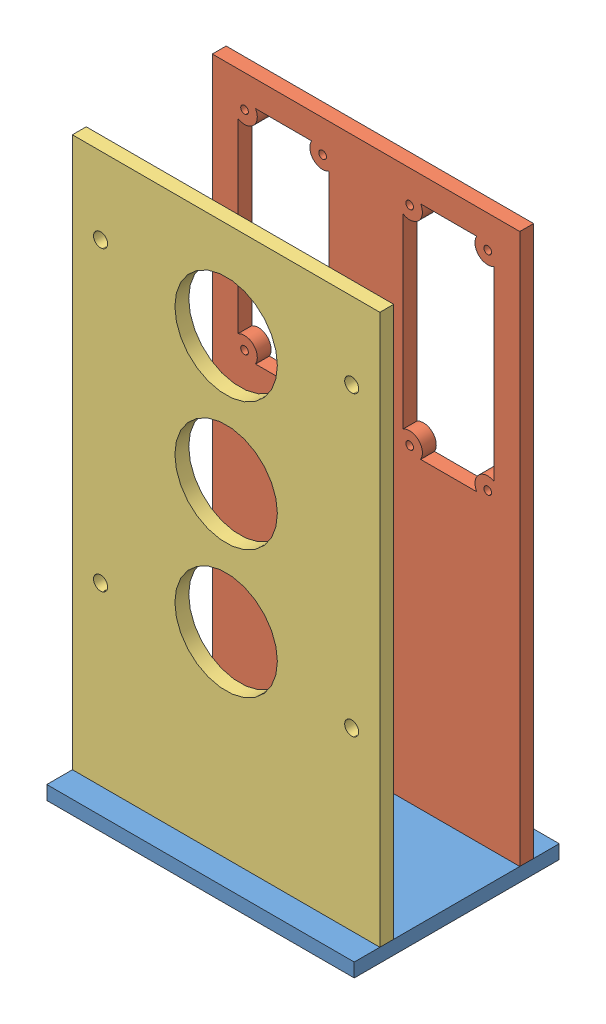
SolidWorks assembly rasp_ard_assem, configuration Varsayılan. Lengths in mm.
Overall size (60 110 40).
3 component instances, 3 part files, 6 mates.
Components (placement in the parent):
- Base-1: Base [Varsayılan] at (-4.139 2.5546 60) size (60 2.7 40)
- Arduino_nano_holder-1: Arduino_nano_holder [Varsayılan] at (-4.0668 54.9672 45) size (60 110 2.7)
- Raspberry_holder-1: Raspberry_holder [Varsayılan] at (-4.139 49.8546 72.3) size (60 110 2.7)
Mates (geometry in assembly coordinates):
- Coincident1: coincident: plane of Base-1 through (13.861 -0.1454 75) normal (0 0 -1); plane of Raspberry_holder-1 through (-4.139 49.8546 75) normal (0 0 1)
- Coincident3: coincident: plane of Base-1 through (-22.139 -0.1454 75) normal (1 0 0); plane of Raspberry_holder-1 through (-22.139 -0.1454 75) normal (-1 0 0)
- Coincident4: coincident aligned: plane of Base-1 through (-4.139 -0.1454 60) normal (0 -1 0); plane of Raspberry_holder-1 through (-10.139 -0.1454 75) normal (0 -1 0)
- Coincident5: coincident: plane of Base-1 through (13.861 -0.1454 47.7) normal (0 0 -1); plane of Arduino_nano_holder-1 through (-4.0668 54.9672 47.7) normal (0 0 1)
- Coincident6: coincident: plane of Base-1 through (25.861 -0.1454 40) normal (1 0 0); plane of Arduino_nano_holder-1 through (25.861 109.8546 47.7) normal (1 0 0)
- Coincident7: coincident aligned: plane of Base-1 through (-4.139 -0.1454 60) normal (0 -1 0); plane of Arduino_nano_holder-1 through (13.861 -0.1454 47.7) normal (0 -1 0)
